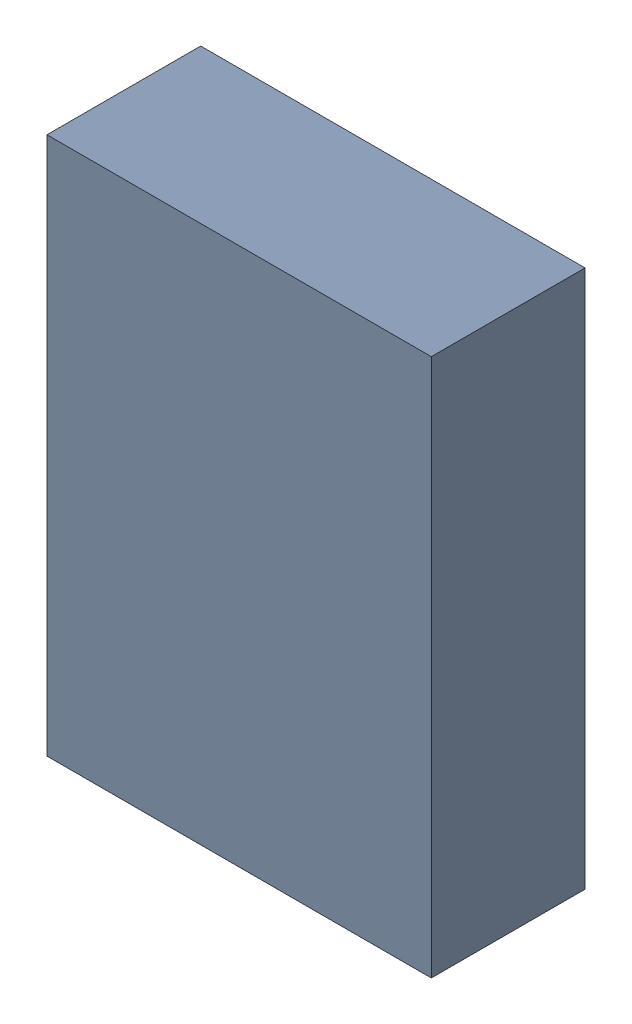
SolidWorks assembly Kanaloa_v2.0.0_Power_1, configuration Default. Lengths in mm.
Overall size (2.5 3.5 1).
2 component instances, 1 part files, 0 mates.
Components (placement in the parent):
- 378153280-1: 378153280 [Default] at (58.3224 144.7546 0) size (2.5 3.5 1)
  - Extruded-1: Extruded [Default] at origin size (2.5 3.5 1)
